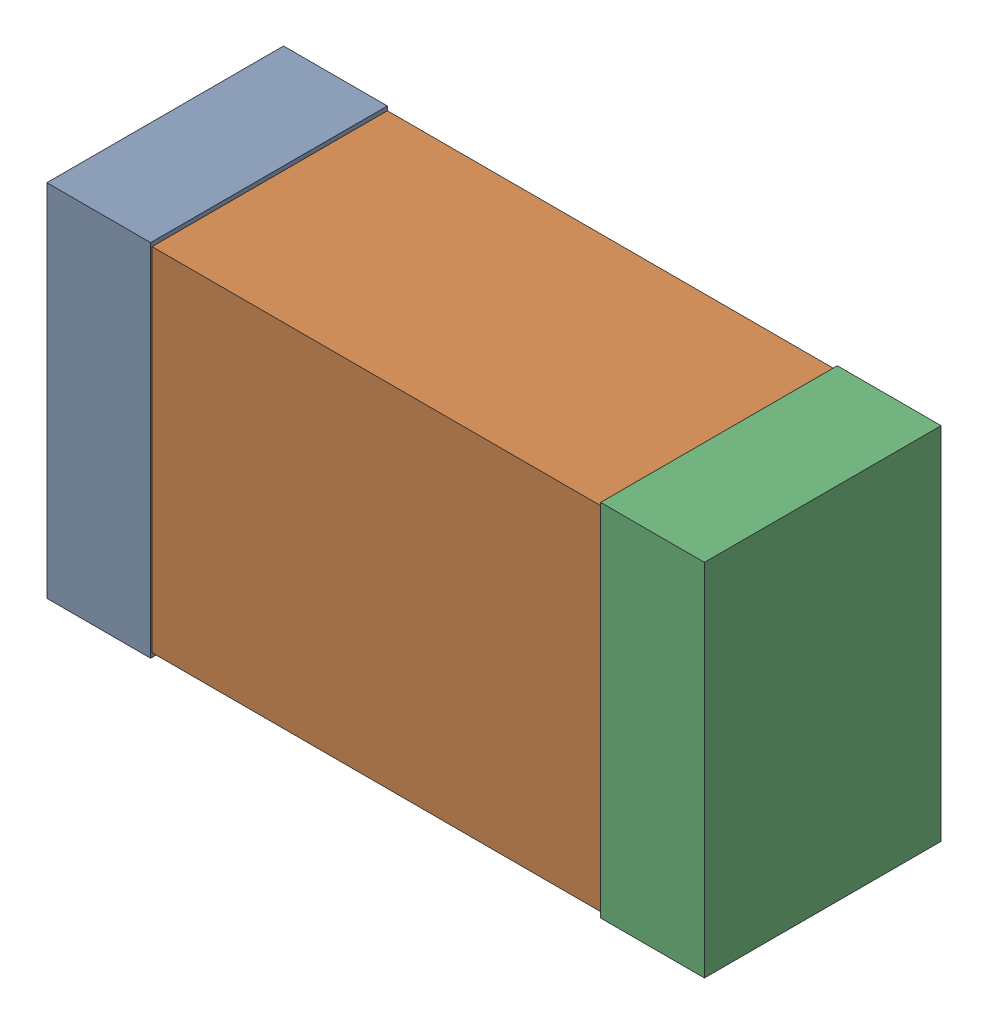
SolidWorks assembly R3_Motor_1Kanaloa_v2.0.0_Motor, configuration Default. Lengths in mm.
Overall size (2.38 1.3 0.85).
6 component instances, 2 part files, 0 mates.
Components (placement in the parent):
- 352877648-1: 352877648 [Default] at (84.344 65.024 0) size (0.38 1.3 0.85)
  - Extruded_14-1: Extruded_14 [Default] at origin size (0.38 1.3 0.85)
- 352877392-1: 352877392 [Default] at (85.344 65.024 0) size (2.2 1.27 0.85)
  - Extruded_15-1: Extruded_15 [Default] at origin size (2.2 1.27 0.85)
- 352877648-2: 352877648 [Default] at (86.344 65.024 0) size (0.38 1.3 0.85)
  - Extruded_14-1: Extruded_14 [Default] at origin size (0.38 1.3 0.85)
